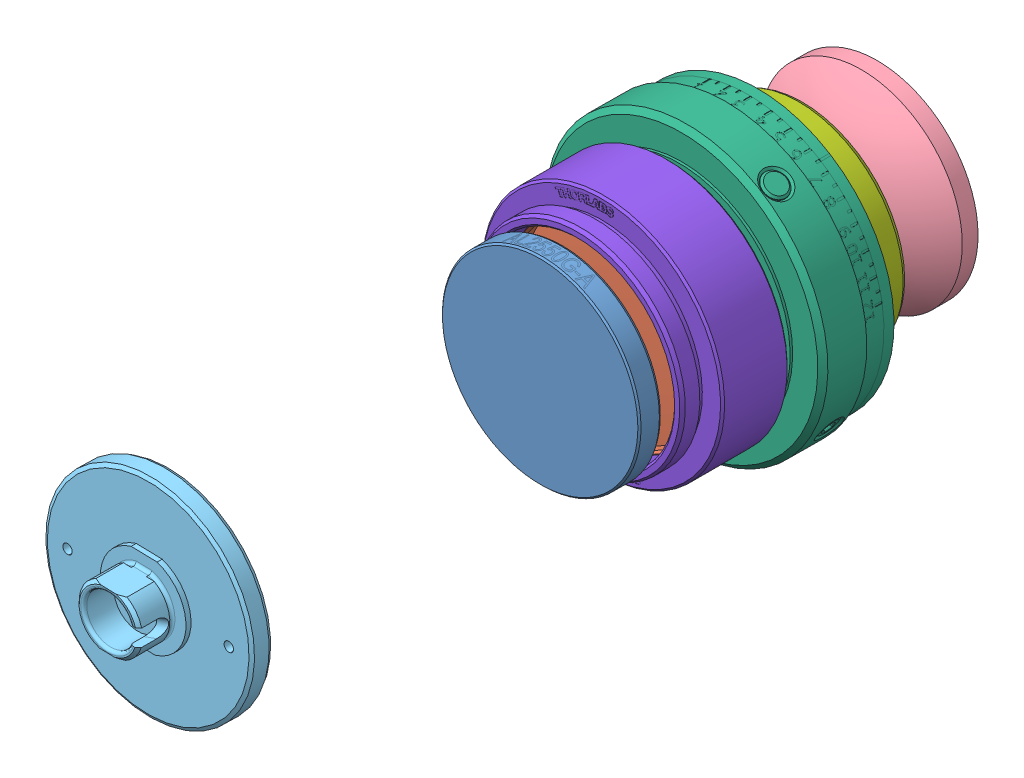
SolidWorks assembly FinalDesign, configuration Default. Lengths in mm.
Overall size (49.21 49.24 96.91).
11 component instances, 11 part files, 20 mates.
Components (placement in the parent):
- AL2550G-A-Solidworks-1: AL2550G-A-Solidworks [Default] at (15.2022 -8.4862 9.6895) size (25 25 5.8)
- LJ1363RM-A-Solidworks-1: LJ1363RM-A-Solidworks [Default] at (1.2489 25.6959 -14.6913) x (0.912145 0.409867 0) z (0.409867 -0.912145 0) size (25.4 5.84 25.4)
- AL1225-A-Solidworks-1: AL1225-A-Solidworks [Default] at (1.2489 25.6959 -30.8423) x (0.941918 -0.335843 0) z (0.335843 0.941918 0) size (12.5 4 12.5)
- LA1422-A-Solidworks-1: LA1422-A-Solidworks [Default] at (1.2489 25.6959 -42.5273) x (0.870544 0.49209 0) z (0 0 1) size (25.4 25.4 6.37)
- SM1FC-Solidworks-1: SM1FC-Solidworks [Default] at (1.2489 25.6959 46.6592) x (0.999689 -0.024954 0) z (0 0 1) size (26.29 26.29 8.28)
- SM1D12C-Solidworks-1: SM1D12C-Solidworks [Default] at (1.2489 25.6959 -23.2257) x (0.847169 -0.531323 0) z (0 0 1) size (35.66 35.76 13.08)
- SM1M30-Solidworks-1: SM1M30-Solidworks [Default] at (1.2489 25.6959 -11.0083) x (-0.994498 0.104757 0) z (0 0 1) size (30.48 30.48 76.2) (hidden)
- SM1A6T-Solidworks-1: SM1A6T-Solidworks [Default] at (1.2489 25.6959 -26.1213) x (0.999773 0.021329 0) z (0 0 1) size (26.29 26.29 10.16)
- SM1M10-Solidworks-1: SM1M10-Solidworks [Default] at (1.2489 25.6959 -56.0933) x (0.999097 0.042477 0) z (0 0 1) size (30.48 30.48 25.4) (hidden)
- SM1M05-Solidworks-1: SM1M05-Solidworks [Default] at (1.2489 25.6959 -47.7443) x (0.999794 -0.020305 0) z (0 0 1) size (30.48 30.48 12.7) (hidden)
- SM1L03-Solidworks-1: SM1L03-Solidworks [Default] at (1.2489 25.6959 -19.3903) x (0 0 -1) z (0.988189 0.153239 0) size (11.43 30.48 30.48)
Mates (geometry in assembly coordinates):
- Concentric1: concentric: cylinder of AL2550G-A-Solidworks-1 through (1.2489 25.6959 -10.6406) axis (0 0 1) radius 12.5; cylinder of LJ1363RM-A-Solidworks-1 through (1.2489 25.6959 -11.7703) axis (0 0 1) radius 12.7
- Concentric2: concentric: cylinder of LJ1363RM-A-Solidworks-1 through (1.2489 25.6959 -11.7703) axis (0 0 1) radius 12.7; cylinder of AL1225-A-Solidworks-1 through (1.2489 25.6959 -30.8423) axis (0 0 1) radius 6.25
- Concentric3: concentric: cylinder of LJ1363RM-A-Solidworks-1 through (1.2489 25.6959 -11.7703) axis (0 0 1) radius 12.7; cylinder of LA1422-A-Solidworks-1 through (1.2489 25.6959 -38.2192) axis (0 0 1) radius 12.7
- Concentric4: concentric: cylinder of LJ1363RM-A-Solidworks-1 through (1.2489 25.6959 -11.7703) axis (0 0 1) radius 12.7; cylinder of SM1FC-Solidworks-1 through (1.2489 25.6959 61.9885) axis (0 0 1) radius 13.1445
- Distance1: distance = 46.183 mm: plane of AL2550G-A-Solidworks-1 through (1.2489 25.6959 -3.2703) normal (0 0 1); plane of SM1FC-Solidworks-1 through (1.3677 30.4569 42.9127) normal (0 0 -1)
- Distance2: distance = 8.5 mm: plane of LJ1363RM-A-Solidworks-1 through (-9.4202 20.9018 -11.7703) normal (0 0 1); plane of AL2550G-A-Solidworks-1 through (1.2489 25.6959 -3.2703) normal (0 0 1)
- Distance3: distance = 18.5 mm: plane of AL1225-A-Solidworks-1 through (7.1359 23.5969 -34.8423) normal (0 0 -1); plane of LJ1363RM-A-Solidworks-1 through (-6.2853 5.8657 -16.3423) normal (0 0 -1)
- Distance4: distance = 10.87 mm: plane of AL1225-A-Solidworks-1 through (7.1359 23.5969 -34.8423) normal (0 0 -1); plane of LA1422-A-Solidworks-1 through (1.2489 25.6959 -45.7123) normal (0 0 -1)
- Concentric5: concentric: cylinder of LJ1363RM-A-Solidworks-1 through (1.2489 25.6959 -11.7703) axis (0 0 1) radius 12.7; cylinder of SM1D12C-Solidworks-1 through (1.2489 25.6959 -17.6123) axis (0 0 -1) radius 13.1445
- Coincident1: coincident: plane of LJ1363RM-A-Solidworks-1 through (-10.3354 20.4906 -17.6123) normal (0 0 -1); plane of SM1D12C-Solidworks-1 through (1.2489 25.6959 -17.6123) normal (0 0 1)
- Concentric6: concentric: cylinder of LJ1363RM-A-Solidworks-1 through (1.2489 25.6959 -11.7703) axis (0 0 1) radius 12.7; cylinder of SM1M30-Solidworks-1 through (1.2489 25.6959 80.617) axis (0 0 1) radius 15.24
- Concentric7: concentric: cylinder of SM1D12C-Solidworks-1 through (1.2489 25.6959 -26.1213) axis (0 0 -1) radius 13.1445; cylinder of SM1A6T-Solidworks-1 through (1.2489 25.6959 -30.9473) axis (0 0 -1) radius 13.1445
- Coincident3: coincident: plane of SM1D12C-Solidworks-1 through (8.3678 37.0467 -26.1213) normal (0 0 -1); plane of SM1A6T-Solidworks-1 through (1.0986 32.7428 -26.1213) normal (0 0 1)
- Concentric8: concentric: cylinder of SM1M30-Solidworks-1 through (1.2489 25.6959 80.617) axis (0 0 1) radius 15.24; cylinder of SM1M10-Solidworks-1 through (1.2489 25.6959 -30.6933) axis (0 0 1) radius 15.24
- Coincident4: coincident: plane of SM1D12C-Solidworks-1 through (1.2489 25.6959 -30.6933) normal (0 0 -1); plane of SM1M10-Solidworks-1 through (0.6015 40.9221 -30.6933) normal (0 0 1)
- Concentric9: concentric: cylinder of SM1M30-Solidworks-1 through (1.2489 25.6959 80.617) axis (0 0 1) radius 15.24; cylinder of SM1M05-Solidworks-1 through (1.2489 25.6959 -35.0443) axis (0 0 1) radius 15.24
- Coincident5: coincident: plane of LA1422-A-Solidworks-1 through (1.2489 25.6959 -45.7123) normal (0 0 -1); plane of SM1M05-Solidworks-1 through (1.2489 25.6959 -45.7123) normal (0 0 1)
- Concentric11: concentric: cylinder of LJ1363RM-A-Solidworks-1 through (1.2489 25.6959 -11.7703) axis (0 0 1) radius 12.7; cylinder of SM1L03-Solidworks-1 through (1.4778 26.9778 -7.013) axis (0 0 -1) radius 15.24
- Coincident8: coincident: plane of LJ1363RM-A-Solidworks-1 through (-9.4202 20.9018 -11.7703) normal (0 0 1); plane of SM1L03-Solidworks-1 through (-0.3613 38.8375 0.607) normal (0 0 -1)
- Coincident9: coincident: plane of SM1M30-Solidworks-1 through (-0.1281 12.6237 -11.0083) normal (0 0 -1); plane of SM1L03-Solidworks-1 through (-1.0865 40.7559 -11.0083) normal (0 0 1)
